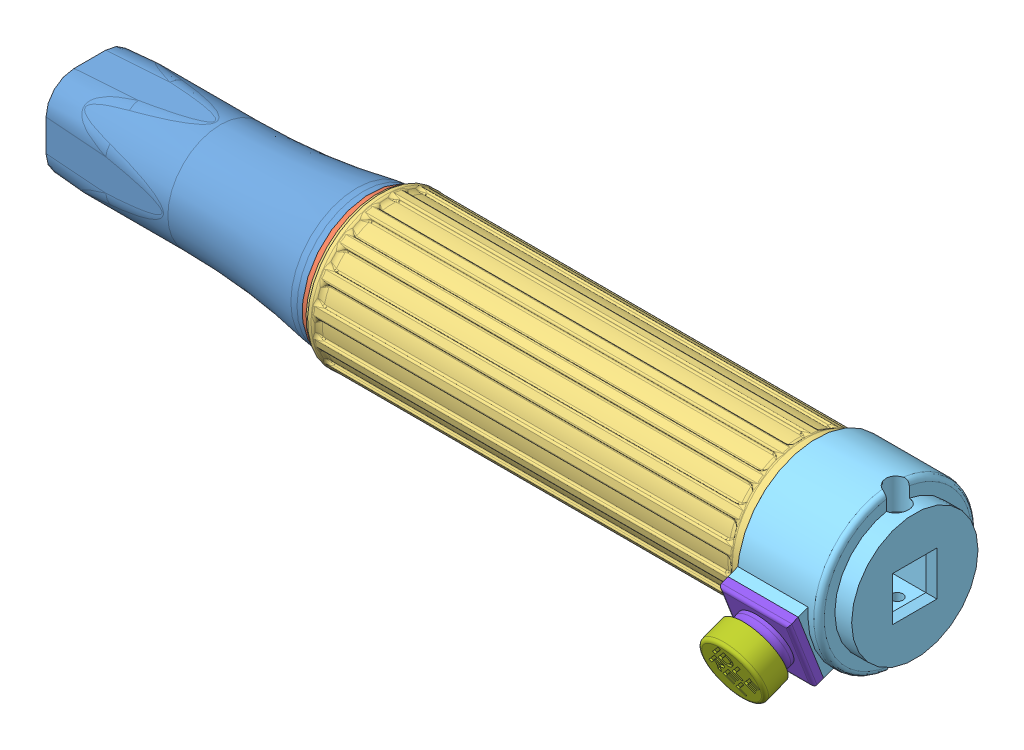
SolidWorks assembly slbe00_SingleCollectiveBodyEvo, configuration Default. Lengths in mm.
Overall size (235 50.81 64.17).
9 component instances, 9 part files, 21 mates.
Components (placement in the parent):
- slbe01_DecorativeCover-3: slbe01_DecorativeCover [По умолчанию] at (-40.1035 -80 -3.8534) x (0 0 -1) z (0 -1 0) size (38 80 38)
- slbe02_ThrottleFrameP1-1: slbe02_ThrottleFrameP1 [По умолчанию] at (96.8965 -80 -3.8534) x (0 1 0) z (0 0 1) size (39 77 39)
- slbe04_ThrottleGrip-1: slbe04_ThrottleGrip [По умолчанию] at (41.8965 -80 -3.8534) x (0 0.972648 0.232285) z (1 0 0) size (42.17 42.17 133.4)
- slbe03_ThrottleFrameP2-1: slbe03_ThrottleFrameP2 [По умолчанию] at (111.8965 -80 -3.8534) x (0 0 1) z (0 1 0) size (36 57 36)
- slbe05_ThrLatchHousingP1-1: slbe05_ThrLatchHousingP1 [По умолчанию] at (166.8965 -80 -3.8534) x (0 1 0) z (0 0 -1) size (45 28 47.7)
- slbe08_ThrLatchBtnP1-1: slbe08_ThrLatchBtnP1 [По умолчанию] at (176.8965 -90.516 23.3397) x (1 0 0) z (0 -0.932688 -0.360684) size (10 5 10)
- slbe09_ThrLatchBtnP2-1: slbe09_ThrLatchBtnP2 [По умолчанию] at (176.8965 -90.6963 23.8061) x (-0.764271 0.601486 0.232603) z (0.644895 0.712826 0.27566) size (18 7 18)
- slbe06_ThrLatchHousingP2-1: slbe06_ThrLatchHousingP2 [По умолчанию] at (176.8965 -88.3519 17.7436) x (1 0 0) z (0 -0.932688 -0.360684) size (20 6 20)
- slbe07_ThrLatchPin-1: slbe07_ThrLatchPin [По умолчанию] at (176.8965 -91.2373 25.2051) x (0 -0.932688 -0.360684) z (1 0 0) size (9 18 7)
Mates (geometry in assembly coordinates):
- Parallel1: parallel anti-aligned: line of slbe01_DecorativeCover-3 through (37.149 -74.85 1.2966) axis (0 -1 0); line of slbe02_ThrottleFrameP1-1 through (42.6439 -85.15 1.2966) axis (0 1 0)
- Coincident7: coincident anti-aligned: plane of slbe01_DecorativeCover-3 through (39.8965 -80 -3.8534) normal (1 0 0); plane of slbe02_ThrottleFrameP1-1 through (39.8965 -80 -3.8534) normal (-1 0 0)
- Concentric1: concentric aligned: circle of slbe01_DecorativeCover-3; cylinder of slbe02_ThrottleFrameP1-1 through (39.8965 -80 -3.8534) axis (1 0 0) radius 19.5
- Concentric2: concentric anti-aligned: cylinder of slbe02_ThrottleFrameP1-1 through (41.8965 -80 -3.8534) axis (1 0 0) radius 18; cylinder of slbe04_ThrottleGrip-1 through (168.2965 -80 -3.8534) axis (-1 0 0) radius 18.3
- Concentric3: concentric anti-aligned: cylinder of slbe02_ThrottleFrameP1-1 through (41.8965 -80 -3.8534) axis (1 0 0) radius 18; cylinder of slbe03_ThrottleFrameP2-1 through (168.8965 -80 -3.8534) axis (-1 0 0) radius 18
- Coincident11: coincident aligned: plane of slbe02_ThrottleFrameP1-1 through (79.8965 -85.15 -9.0034) normal (0 0 1); plane of slbe03_ThrottleFrameP2-1 through (168.8965 -74.85 -9.0034) normal (0 0 1)
- Coincident12: coincident anti-aligned: plane of slbe02_ThrottleFrameP1-1 through (111.8965 -80 -3.8534) normal (1 0 0); plane of slbe03_ThrottleFrameP2-1 through (111.8965 -80 -3.8534) normal (-1 0 0)
- Coincident13: coincident anti-aligned: plane of slbe02_ThrottleFrameP1-1 through (41.8965 -80 -3.8534) normal (1 0 0); plane of slbe04_ThrottleGrip-1 through (41.8965 -80 -3.8534) normal (-1 0 0)
- Concentric4: concentric anti-aligned: circle of slbe03_ThrottleFrameP2-1; cylinder of slbe05_ThrLatchHousingP1-1 through (194.8965 -80 -3.8534) axis (-1 0 0) radius 22.5
- Parallel2: parallel aligned: plane of slbe03_ThrottleFrameP2-1 through (168.8965 -74.85 -9.0034) normal (0 0 1); plane of slbe05_ThrLatchHousingP1-1 through (194.8965 -74.85 -9.0034) normal (0 0 1)
- Coincident15: coincident anti-aligned: plane of slbe03_ThrottleFrameP2-1 through (168.8965 -80 -3.8534) normal (1 0 0); plane of slbe05_ThrLatchHousingP1-1 through (168.8965 -80 -3.8534) normal (-1 0 0)
- Concentric5: concentric anti-aligned: cylinder of slbe05_ThrLatchHousingP1-1 through (176.8965 -82.5809 2.8206) axis (0 -0.360684 0.932688) radius 3.8; cylinder of slbe06_ThrLatchHousingP2-1 through (176.8965 -89.4339 20.5417) axis (0 0.360684 -0.932688) radius 3.8
- Coincident16: coincident anti-aligned: plane of slbe05_ThrLatchHousingP1-1 through (186.8965 -97.6788 14.1368) normal (0 -0.360684 0.932688); plane of slbe06_ThrLatchHousingP2-1 through (176.8965 -88.3519 17.7436) normal (0 0.360684 -0.932688)
- Concentric6: concentric aligned: cylinder of slbe05_ThrLatchHousingP1-1 through (176.8965 -82.5809 2.8206) axis (0 -0.360684 0.932688) radius 3.8; cylinder of slbe07_ThrLatchPin-1 through (176.8965 -84.745 8.4167) axis (0 -0.360684 0.932688) radius 3.5
- Parallel3: parallel aligned: plane of slbe05_ThrLatchHousingP1-1 through (178.8965 -80 -3.8534) normal (-1 0 0); plane of slbe07_ThrLatchPin-1 through (175.8965 -92.549 16.1205) normal (-1 0 0)
- Coincident18: coincident anti-aligned: plane of slbe06_ThrLatchHousingP2-1 through (176.8965 -88.3519 17.7436) normal (0 0.360684 -0.932688); plane of slbe07_ThrLatchPin-1 through (176.8965 -88.3519 17.7436) normal (0 -0.360684 0.932688)
- Coincident19: coincident anti-aligned: plane of slbe08_ThrLatchBtnP1-1 through (176.8965 -91.2373 25.2051) normal (0 0.360684 -0.932688); plane of slbe07_ThrLatchPin-1 through (176.8965 -91.2373 25.2051) normal (0 -0.360684 0.932688)
- Concentric8: concentric anti-aligned: cylinder of slbe08_ThrLatchBtnP1-1 through (176.8965 -91.2373 25.2051) axis (0 0.360684 -0.932688) radius 3.7; cylinder of slbe07_ThrLatchPin-1 through (176.8965 -84.745 8.4167) axis (0 -0.360684 0.932688) radius 3.5
- Coincident20: coincident anti-aligned: plane of slbe08_ThrLatchBtnP1-1 through (176.8965 -92.3194 28.0032) normal (0 -0.360684 0.932688); plane of slbe09_ThrLatchBtnP2-1 through (176.8965 -92.3194 28.0032) normal (0 0.360684 -0.932688)
- Concentric9: concentric aligned: cylinder of slbe08_ThrLatchBtnP1-1 through (176.8965 -92.3194 28.0032) axis (0 0.360684 -0.932688) radius 5; cylinder of slbe09_ThrLatchBtnP2-1 through (176.8965 -93.2211 30.3349) axis (0 0.360684 -0.932688) radius 9
- Coincident21: coincident aligned: plane of slbe05_ThrLatchHousingP1-1 through (186.8965 -96.5967 11.3387) normal (0 -0.932688 -0.360684); plane of slbe06_ThrLatchHousingP2-1 through (186.8965 -98.7608 16.9348) normal (0 -0.932688 -0.360684)
